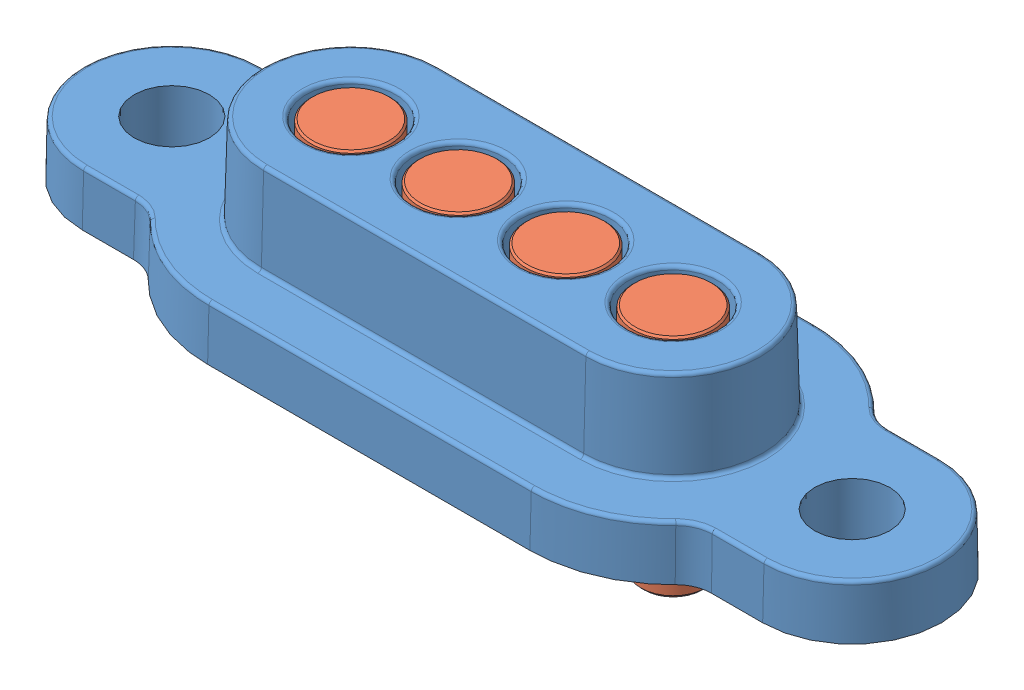
SolidWorks assembly SWIFT DOCK MINI-4-L, configuration Défaut. Lengths in mm.
Overall size (24 6.56 8).
5 component instances, 2 part files, 0 mates.
Components (placement in the parent):
- land body_4 hole_mini-1: land body_4 hole_mini [Défaut] at origin size (24 4.81 8)
- contact land_sd_mini-1: contact land_sd_mini [Défaut] at (0 3.94 0) x (1 0 0) z (0 1 0) size (2.23 2.23 6.5)
- contact land_sd_mini-2: contact land_sd_mini [Défaut] at (3 3.94 0) x (1 0 0) z (0 1 0) size (2.23 2.23 6.5)
- contact land_sd_mini-3: contact land_sd_mini [Défaut] at (6 3.94 0) x (1 0 0) z (0 1 0) size (2.23 2.23 6.5)
- contact land_sd_mini-4: contact land_sd_mini [Défaut] at (9 3.94 0) x (1 0 0) z (0 1 0) size (2.23 2.23 6.5)
